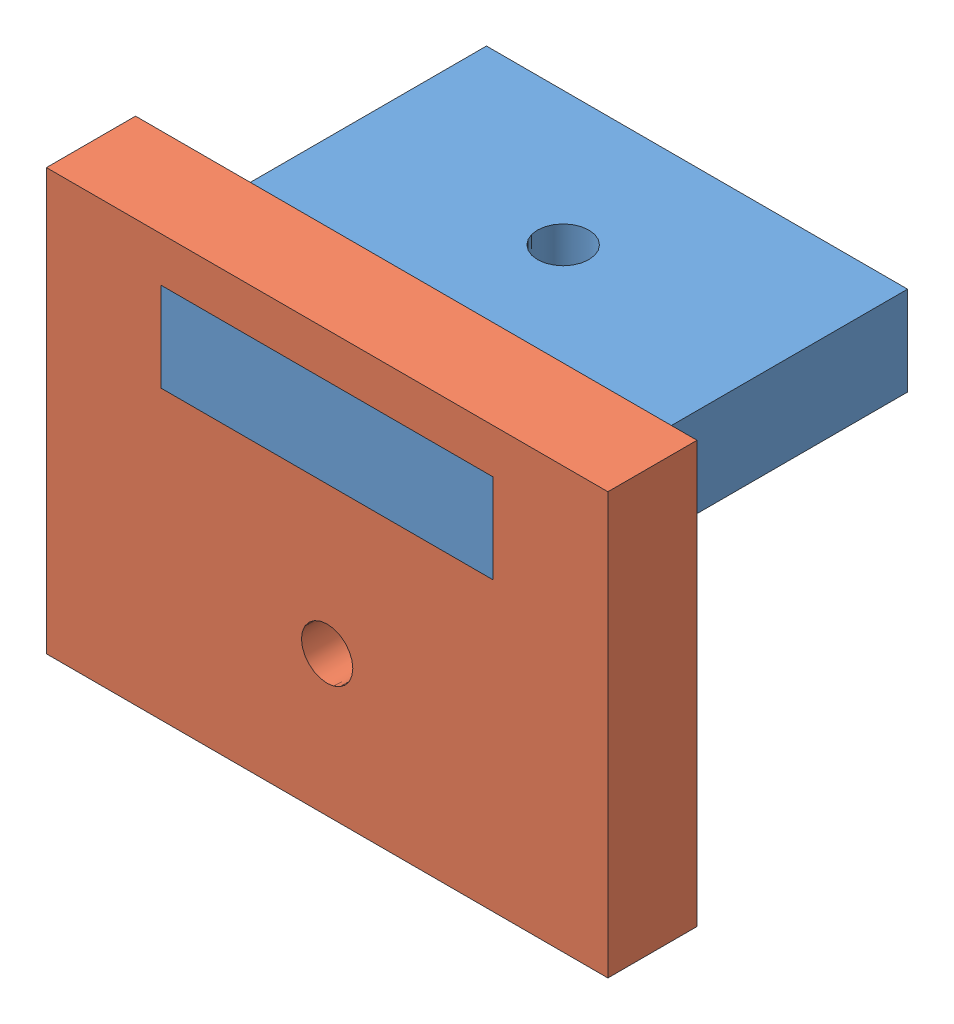
SolidWorks assembly Assem1, configuration Default. Lengths in mm.
Overall size (40 30 26.35).
3 component instances, 3 part files, 6 mates.
Components (placement in the parent):
- test one-1: test one [Default] at (6.4923 11.0786 23.2883) size (30 6.35 26.35)
- test two-1: test two [Default] at (6.4923 5.6036 33.2883) x (1 0 0) z (0 -1 0) size (40 6.35 30)
- 6-32 angle bracket-1: 6-32 angle bracket [Default] at (12.8423 -3.1962 33.2883) x (0 1 0) z (-1 0 0) size (14.27 14.27 12.7)
Mates (geometry in assembly coordinates):
- Coincident1: coincident anti-aligned: plane of test one-1 through (6.4923 17.4286 23.2883) normal (0 1 0); plane of test two-1 through (-5.3277 17.4286 33.2883) normal (0 -1 0)
- Coincident2: coincident anti-aligned: plane of test one-1 through (-5.3277 17.4286 39.6383) normal (-1 0 0); plane of test two-1 through (-5.3277 11.0786 33.2883) normal (1 0 0)
- Coincident3: coincident aligned: plane of test one-1 through (-5.3277 17.4286 39.6383) normal (0 0 1); plane of test two-1 through (6.4923 5.6036 39.6383) normal (0 0 1)
- Coincident4: coincident anti-aligned: plane of test two-1 through (6.4923 5.6036 33.2883) normal (0 0 -1); plane of 6-32 angle bracket-1 through (0.1423 -3.1962 33.2883) normal (0 0 1)
- Coincident5: coincident anti-aligned: plane of test one-1 through (6.4923 11.0786 23.2883) normal (0 -1 0); plane of 6-32 angle bracket-1 through (0.1423 11.0786 33.2883) normal (0 1 0)
- Concentric1: concentric anti-aligned: cylinder of test one-1 through (6.4923 17.4286 22.8235) axis (0 1 0) radius 1.8288; circle of 6-32 angle bracket-1
